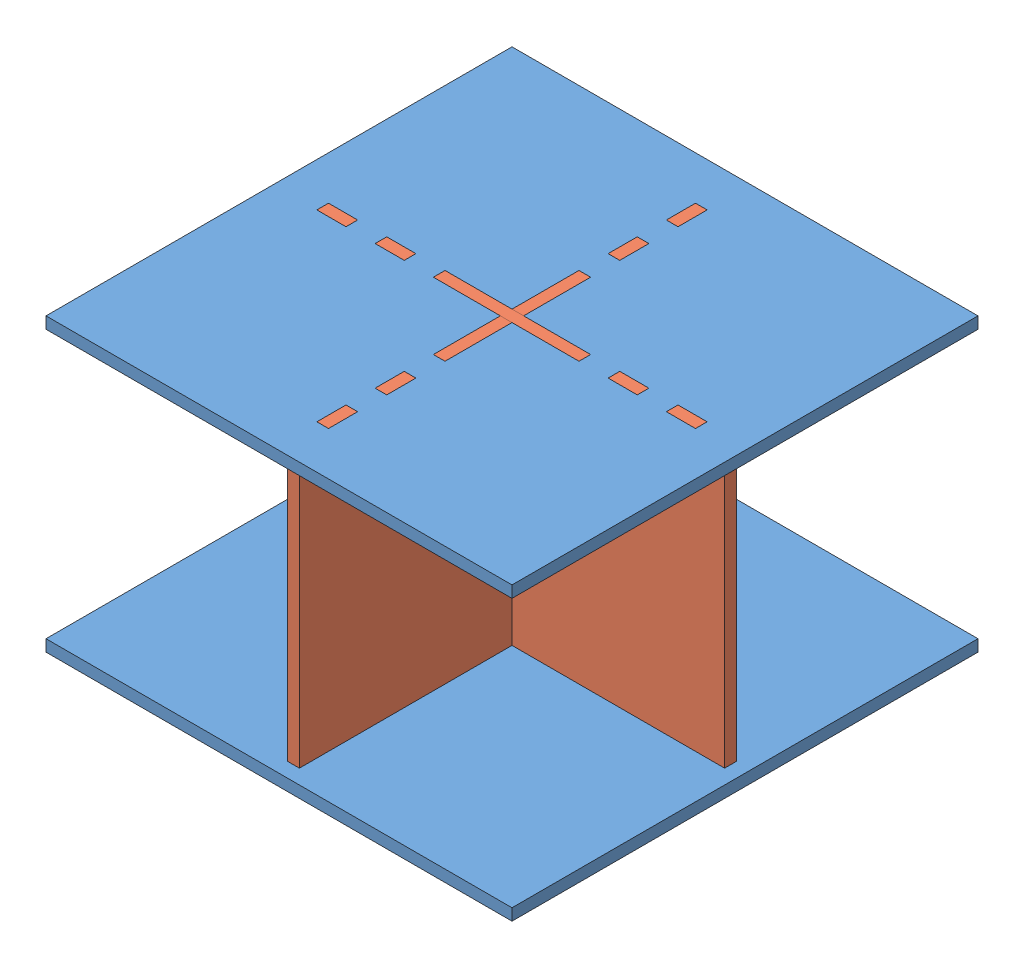
SolidWorks assembly RobotStand, configuration Default. Lengths in mm.
Overall size (160 100 160).
4 component instances, 2 part files, 6 mates.
Components (placement in the parent):
- HorizontalPanel-1: HorizontalPanel [Default] at (61.7593 76.7614 126.3154) size (160 4 160)
- VerticalPanel-1: VerticalPanel [Default] at (61.7593 126.7614 124.3154) size (150 100 4)
- HorizontalPanel-2: HorizontalPanel [Default] at (61.7593 172.7614 126.3154) size (160 4 160)
- VerticalPanel-2: VerticalPanel [Default] at (63.7593 126.7614 126.3154) x (0 0 -1) z (-1 0 0) size (150 100 4)
Mates (geometry in assembly coordinates):
- Coincident1: coincident anti-aligned: line of HorizontalPanel-1 through (63.7593 76.7614 151.3154) axis (0 0 -1); line of VerticalPanel-2 through (63.7593 76.7614 101.3154) axis (0 0 1)
- Coincident2: coincident anti-aligned: line of HorizontalPanel-1 through (59.7593 76.7614 151.3154) axis (1 0 0); line of VerticalPanel-2 through (63.7593 76.7614 151.3154) axis (-1 0 0)
- Coincident3: coincident anti-aligned: line of HorizontalPanel-1 through (86.7593 76.7614 128.3154) axis (0 0 -1); line of VerticalPanel-1 through (86.7593 76.7614 124.3154) axis (0 0 1)
- Coincident4: coincident aligned: line of HorizontalPanel-1 through (63.7593 76.7614 128.3154) axis (1 0 0); line of VerticalPanel-1 through (63.7593 76.7614 128.3154) axis (1 0 0)
- Coincident5: coincident anti-aligned: line of HorizontalPanel-2 through (63.7593 176.7614 126.3154) axis (0 0 1); line of VerticalPanel-2 through (63.7593 176.7614 151.3154) axis (0 0 -1)
- Coincident6: coincident aligned: line of VerticalPanel-1 through (86.7593 176.7614 124.3154) axis (-1 0 0); line of HorizontalPanel-2 through (59.7593 176.7614 124.3154) axis (-1 0 0)
